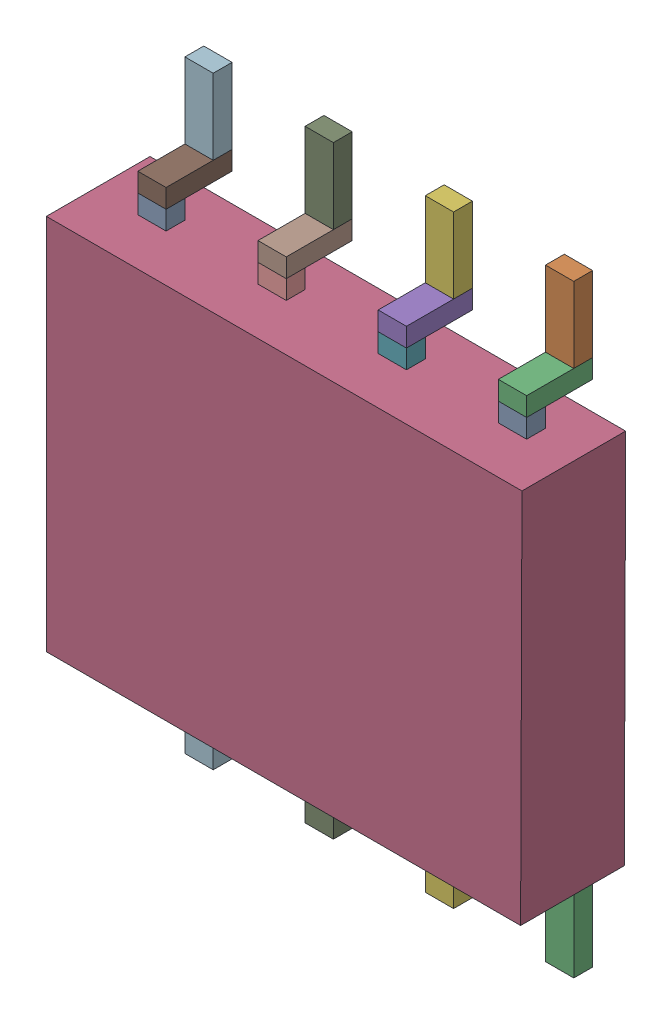
SolidWorks assembly U5, configuration Default. Lengths in mm.
Overall size (5.05 6.4 1.2).
50 component instances, 4 part files, 0 mates.
Components (placement in the parent):
- 836754544-1: 836754544 [Default] at (133.1 14.75 0.5) size (0.3 0.2 0.2)
  - Extruded_35-1: Extruded_35 [Default] at origin size (0.3 0.2 0.2)
- 810371856-1: 810371856 [Default] at (133.1 15.45 0) size (0.3 0.8 0.2)
  - Extruded_36-1: Extruded_36 [Default] at origin size (0.3 0.8 0.2)
- 836754160-1: 836754160 [Default] at (133.1 14.95 0) size (0.3 0.2 0.7)
  - Extruded_37-1: Extruded_37 [Default] at origin size (0.3 0.2 0.7)
- 1070555888-1: 1070555888 [Default] at (131.1778 12.65 0.1) size (5.05 4 1.1)
  - Extruded_38-1: Extruded_38 [Default] at origin size (5.05 4 1.1)
- 836754160-2: 836754160 [Default] at (131.825 14.95 0) size (0.3 0.2 0.7)
  - Extruded_37-1: Extruded_37 [Default] at origin size (0.3 0.2 0.7)
- 810371856-2: 810371856 [Default] at (131.825 15.45 0) size (0.3 0.8 0.2)
  - Extruded_36-1: Extruded_36 [Default] at origin size (0.3 0.8 0.2)
- 836754544-2: 836754544 [Default] at (131.825 14.75 0.5) size (0.3 0.2 0.2)
  - Extruded_35-1: Extruded_35 [Default] at origin size (0.3 0.2 0.2)
- 836754160-3: 836754160 [Default] at (130.55 14.95 0) size (0.3 0.2 0.7)
  - Extruded_37-1: Extruded_37 [Default] at origin size (0.3 0.2 0.7)
- 810371856-3: 810371856 [Default] at (130.55 15.45 0) size (0.3 0.8 0.2)
  - Extruded_36-1: Extruded_36 [Default] at origin size (0.3 0.8 0.2)
- 836754544-3: 836754544 [Default] at (130.55 14.75 0.5) size (0.3 0.2 0.2)
  - Extruded_35-1: Extruded_35 [Default] at origin size (0.3 0.2 0.2)
- 836754160-4: 836754160 [Default] at (129.275 14.95 0) size (0.3 0.2 0.7)
  - Extruded_37-1: Extruded_37 [Default] at origin size (0.3 0.2 0.7)
- 810371856-4: 810371856 [Default] at (129.275 15.45 0) size (0.3 0.8 0.2)
  - Extruded_36-1: Extruded_36 [Default] at origin size (0.3 0.8 0.2)
- 836754544-4: 836754544 [Default] at (129.275 14.75 0.5) size (0.3 0.2 0.2)
  - Extruded_35-1: Extruded_35 [Default] at origin size (0.3 0.2 0.2)
- 836754544-5: 836754544 [Default] at (133.1 10.55 0.5) size (0.3 0.2 0.2)
  - Extruded_35-1: Extruded_35 [Default] at origin size (0.3 0.2 0.2)
- 810371856-5: 810371856 [Default] at (133.1 9.85 0) size (0.3 0.8 0.2)
  - Extruded_36-1: Extruded_36 [Default] at origin size (0.3 0.8 0.2)
- 836754160-5: 836754160 [Default] at (133.1 10.35 0) size (0.3 0.2 0.7)
  - Extruded_37-1: Extruded_37 [Default] at origin size (0.3 0.2 0.7)
- 836754544-6: 836754544 [Default] at (131.825 10.55 0.5) size (0.3 0.2 0.2)
  - Extruded_35-1: Extruded_35 [Default] at origin size (0.3 0.2 0.2)
- 810371856-6: 810371856 [Default] at (131.825 9.85 0) size (0.3 0.8 0.2)
  - Extruded_36-1: Extruded_36 [Default] at origin size (0.3 0.8 0.2)
- 836754160-6: 836754160 [Default] at (131.825 10.35 0) size (0.3 0.2 0.7)
  - Extruded_37-1: Extruded_37 [Default] at origin size (0.3 0.2 0.7)
- 836754544-7: 836754544 [Default] at (130.55 10.55 0.5) size (0.3 0.2 0.2)
  - Extruded_35-1: Extruded_35 [Default] at origin size (0.3 0.2 0.2)
- 810371856-7: 810371856 [Default] at (130.55 9.85 0) size (0.3 0.8 0.2)
  - Extruded_36-1: Extruded_36 [Default] at origin size (0.3 0.8 0.2)
- 836754160-7: 836754160 [Default] at (130.55 10.35 0) size (0.3 0.2 0.7)
  - Extruded_37-1: Extruded_37 [Default] at origin size (0.3 0.2 0.7)
- 836754160-8: 836754160 [Default] at (129.275 10.35 0) size (0.3 0.2 0.7)
  - Extruded_37-1: Extruded_37 [Default] at origin size (0.3 0.2 0.7)
- 810371856-8: 810371856 [Default] at (129.275 9.85 0) size (0.3 0.8 0.2)
  - Extruded_36-1: Extruded_36 [Default] at origin size (0.3 0.8 0.2)
- 836754544-8: 836754544 [Default] at (129.275 10.55 0.5) size (0.3 0.2 0.2)
  - Extruded_35-1: Extruded_35 [Default] at origin size (0.3 0.2 0.2)
